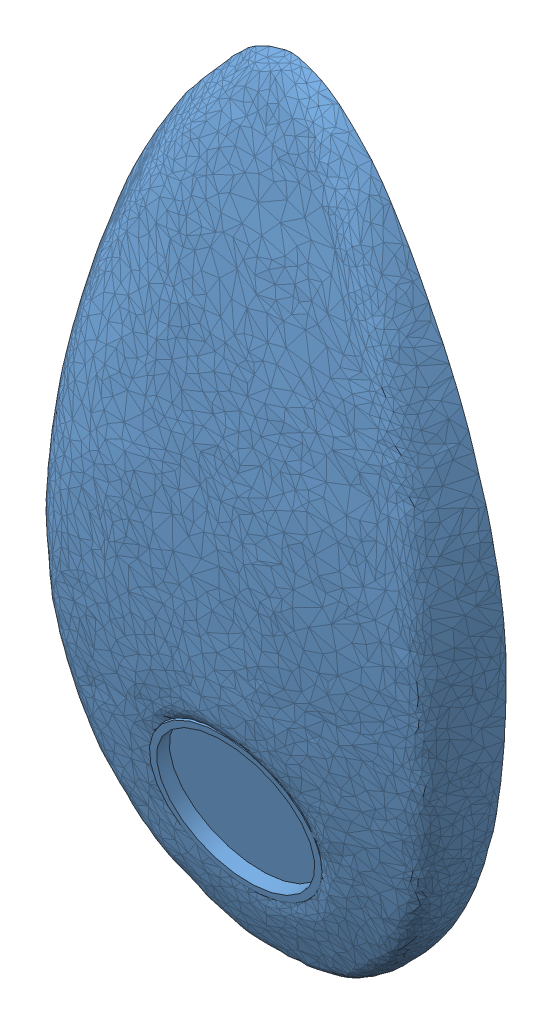
SolidWorks assembly Assem10, configuration Default. Lengths in mm.
Overall size (73.7 119.76 20).
2 component instances, 2 part files, 4 mates.
Components (placement in the parent):
- part_housingPrepared-1: part_housingPrepared [Default] at (1.4093 9.2175 -30.0595) size (64.09 119.76 15.04)
- housing-1: housing [Default] at (4.8863 -42.8578 -7.1848) x (0.408808 0.912584 -0.008176) z (-0.904021 0.406167 0.133324) size (60.5 8.65 49)
Mates (geometry in assembly coordinates):
- Parallel1: parallel: plane of part_housingPrepared-1 through (-1.6236 -37.4871 -0.1824) normal (0.037263 -0.23582 0.971082); plane of housing-1 through (5.0469 -43.8743 -2.999) normal (0.037263 -0.23582 0.971082)
- Coincident2: coincident: plane of part_housingPrepared-1 through (-1.6236 -37.4871 -0.1824) normal (0.037263 -0.23582 0.971082); line of housing-1 through (-10.2059 -43.3076 -1.2666) axis (0.904021 -0.406167 -0.133324)
- Coincident3: coincident: line of part_housingPrepared-1 through (-1.4909 -38.3264 3.2736) axis (-0.037263 0.23582 -0.971082); point of housing-1
- Parallel2: parallel anti-aligned: line of part_housingPrepared-1 through (7.524 -35.4721 3.6208) axis (-0.904021 0.406167 0.133324); line of housing-1 through (-10.2059 -43.3076 -1.2666) axis (0.904021 -0.406167 -0.133324)
